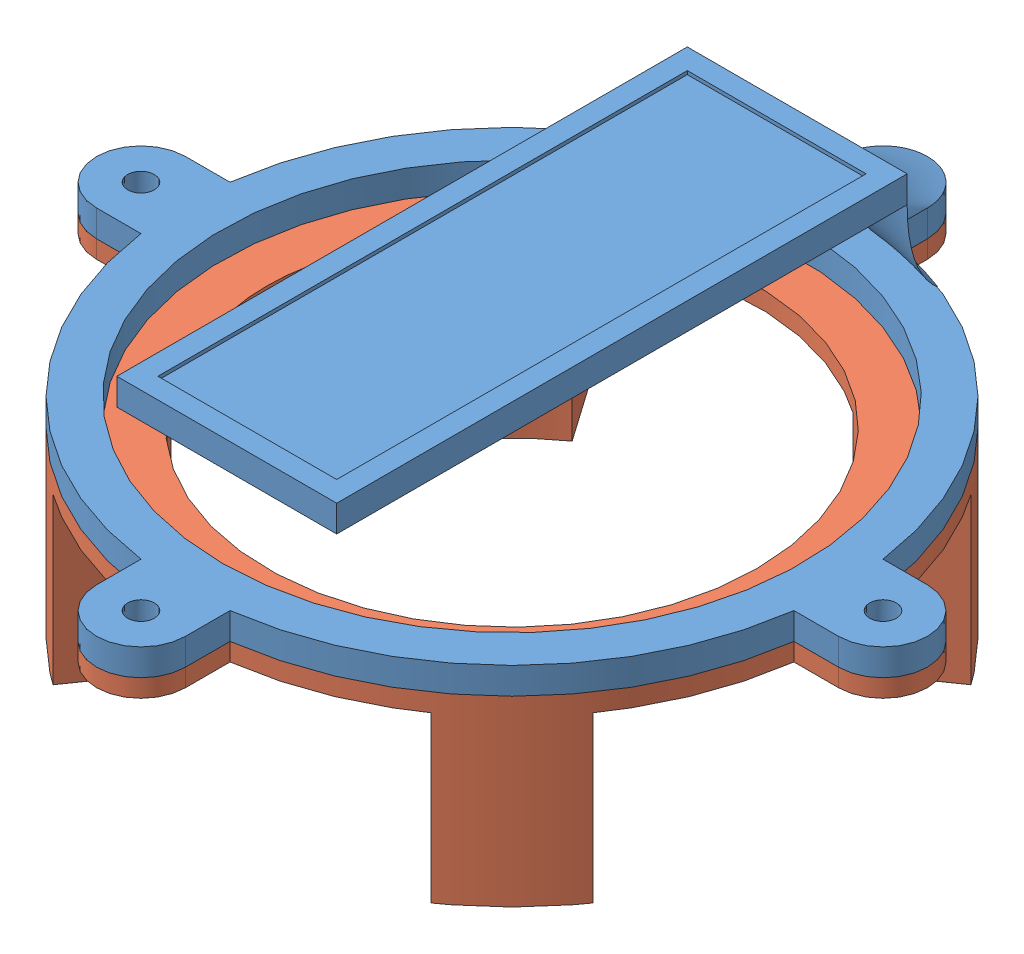
SolidWorks assembly Microscope_Slide_Stand, configuration Default. Lengths in mm.
Overall size (118.52 44.83 118.69).
2 component instances, 2 part files, 4 mates.
Components (placement in the parent):
- Slide_Holder-1: Slide_Holder [Default] at (67.4847 69.8419 73.2764) size (118.52 18.8 118.69)
- Stand_Base^Microscope_Slide_Stand-1: Stand_Base^Microscope_Slide_Stand [Default] at (67.4847 69.8419 73.2764) x (-1 0 0) z (0 -1 0) size (118.52 118.52 26.04) (virtual)
Mates (geometry in assembly coordinates):
- InPlace1: in place: plane of Slide_Holder-1 through (67.4847 69.8419 73.2764) normal (0 -1 0); plane of ? through (0 69.8419 0) normal (0 -1 0); moOrthogonalPlaneRef_w of Slide_Holder-1 through (67.4847 69.8419 73.2764) normal (0 -1 0); unknown of ?; plane of Slide_Holder-1 through (67.4847 69.8419 73.2764) normal (0 -1 0); line of ? through (-55 0 69.8419) axis (0 -1 0); plane of Slide_Holder-1 through (67.4847 69.8419 73.2764) normal (0 -1 0); unknown of Stand_Base^Microscope_Slide_Stand-1
- Coincident2: coincident aligned: plane of Slide_Holder-1; plane of Stand_Base^Microscope_Slide_Stand-1
- Coincident3: coincident aligned: moOrthogonalPlaneRef_w of Slide_Holder-1 through (67.4847 69.8419 73.2764) normal (0 0 -1); plane of Stand_Base^Microscope_Slide_Stand-1
- Coincident4: coincident anti-aligned: moOrthogonalPlaneRef_w of Slide_Holder-1 through (67.4847 69.8419 73.2764) normal (1 0 0); plane of Stand_Base^Microscope_Slide_Stand-1
